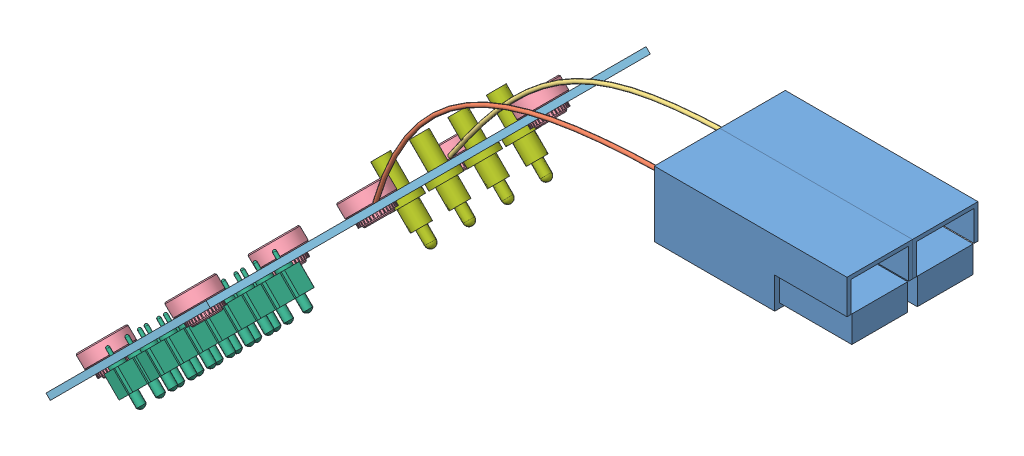
SolidWorks assembly AU-SK-100-000494, configuration Default. Lengths in mm.
Overall size (144.45 105.44 132.78).
17 component instances, 7 part files, 3 mates.
Components (placement in the parent):
- AU-SK-1-000249-1: AU-SK-1-000249 [Default] at (90.6703 82.4308 -22.9944) x (0 0 1) z (-1 -0.00005 0) size (17.27 8.64 25.4)
- AU-SK-1-000615-1: AU-SK-1-000615 [Default] at (55.9151 53.7792 -42.3665) size (54 22.81 0.51)
- AU-SK-1-000614-1: AU-SK-1-000614 [Default] at (56.8933 45.7752 -44.5778) size (52.76 21.32 0.51)
- AU-SK-1-000592-1: AU-SK-1-000592 [95117A411] at (18.1101 50.4596 -56.7407) x (0.5 0.5 0.707107) z (-0.707107 0.707107 0) size (5.59 5.59 3.59)
- AU-SK-1-000592-2: AU-SK-1-000592 [95117A411] at (6.4358 38.7852 -56.7407) x (0.5 0.5 0.707107) z (-0.707107 0.707107 0) size (5.59 5.59 3.59)
- AU-SK-1-000592-3: AU-SK-1-000592 [95117A411] at (18.1101 50.4596 -34.0839) x (0.5 0.5 0.707107) z (-0.707107 0.707107 0) size (5.59 5.59 3.59)
- AU-SK-1-000592-4: AU-SK-1-000592 [95117A411] at (6.4358 38.7852 -34.0839) x (0.5 0.5 0.707107) z (-0.707107 0.707107 0) size (5.59 5.59 3.59)
- AU-SK-1-000592-5: AU-SK-1-000592 [95117A411] at (18.1101 50.4596 -11.4271) x (0.5 0.5 0.707107) z (-0.707107 0.707107 0) size (5.59 5.59 3.59)
- AU-SK-1-000592-6: AU-SK-1-000592 [95117A411] at (6.4358 38.7852 -11.4271) x (0.5 0.5 0.707107) z (-0.707107 0.707107 0) size (5.59 5.59 3.59)
- AU-SK-2-000791-1: AU-SK-2-000791 [Default] at (29.3531 69.1902 -54.4746) size (81.07 81.07 132.78)
  - AU-SK-1-000449-1: AU-SK-1-000449 [Default] at (-82.5713 -93.6909 -83.1375) x (0 0 1) z (-0.707107 0.707107 0) size (132.78 113.86 0.79)
  - AU-SK-1-000590-1: AU-SK-1-000590 [Default] at (-11.8156 -27.4433 32.3933) x (0 0 -1) z (-0.707107 -0.707107 0) size (20.32 6.76 2.54)
  - AU-SK-1-000080-1: AU-SK-1-000080 [Default] at (-18.3223 -23.3313 -4.3851) x (0.658834 0.658834 -0.363148) z (-0.256784 -0.256784 -0.931732) size (3.81 9.91 3.81)
  - AU-SK-1-000080-2: AU-SK-1-000080 [Default] at (-18.3203 -23.3333 0.6949) x (-0.707107 -0.707107 0) z (0 0 1) size (3.81 9.91 3.81)
  - AU-SK-1-000080-3: AU-SK-1-000080 [Default] at (-18.3203 -23.3333 5.7749) x (-0.707107 -0.707107 0) z (0 0 1) size (3.81 9.91 3.81)
  - AU-SK-1-000080-4: AU-SK-1-000080 [Default] at (-18.3203 -23.3333 10.8549) x (-0.707107 -0.707107 0) z (0 0 1) size (3.81 9.91 3.81)
  - AU-SK-1-000590-2: AU-SK-1-000590 [Default] at (-16.0064 -31.6341 32.3933) x (0 0 -1) z (-0.707107 -0.707107 0) size (20.32 6.76 2.54)
Mates (geometry in assembly coordinates):
- Lock1: lock: unknown of AU-SK-1-000614-1; unknown of AU-SK-1-000615-1
- Lock2: lock: unknown of AU-SK-1-000614-1; unknown of AU-SK-1-000249-1
- Lock3: lock: unknown of AU-SK-1-000614-1; unknown of AU-SK-1-000249-1
